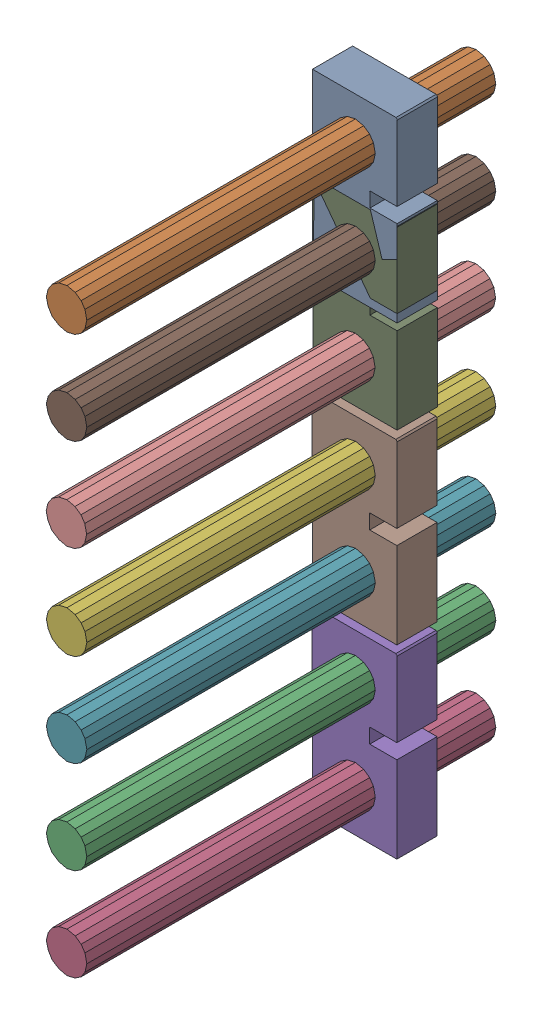
SolidWorks assembly P3, configuration Default. Lengths in mm.
Overall size (2.33 17.58 11.2).
22 component instances, 2 part files, 0 mates.
Components (placement in the parent):
- 432125072-1: 432125072 [Default] at (25.1917 44.8391 0) size (2.33 4.86 1.1)
  - Extruded (13)-1: Extruded (13) [Default] at origin size (2.33 4.86 1.1)
- 432124688-1: 432124688 [Default] at (25.1948 46.1265 -2.2) size (1.11 1.11 11.2)
  - Extruded (14)-1: Extruded (14) [Default] at origin size (1.11 1.11 11.2)
- 432124688_1-1: 432124688_1 [Default] at (25.1954 33.4054 -2.2) size (1.11 1.11 11.2)
  - Extruded (14)-1: Extruded (14) [Default] at origin size (1.11 1.11 11.2)
- 432124688_2-1: 432124688_2 [Default] at (25.1954 30.8654 -2.2) size (1.11 1.11 11.2)
  - Extruded (14)-1: Extruded (14) [Default] at origin size (1.11 1.11 11.2)
- 432125072_1-1: 432125072_1 [Default] at (25.1858 32.1222 0) size (2.33 4.86 1.1)
  - Extruded (13)-1: Extruded (13) [Default] at origin size (2.33 4.86 1.1)
- 432124688_3-1: 432124688_3 [Default] at (25.1954 38.4854 -2.2) size (1.11 1.11 11.2)
  - Extruded (14)-1: Extruded (14) [Default] at origin size (1.11 1.11 11.2)
- 432124688_4-1: 432124688_4 [Default] at (25.1954 35.9454 -2.2) size (1.11 1.11 11.2)
  - Extruded (14)-1: Extruded (14) [Default] at origin size (1.11 1.11 11.2)
- 432125072_2-1: 432125072_2 [Default] at (25.1858 37.2022 0) size (2.33 4.86 1.1)
  - Extruded (13)-1: Extruded (13) [Default] at origin size (2.33 4.86 1.1)
- 432125072_3-1: 432125072_3 [Default] at (25.1917 42.2991 0) size (2.33 4.86 1.1)
  - Extruded (13)-1: Extruded (13) [Default] at origin size (2.33 4.86 1.1)
- 432124688_5-1: 432124688_5 [Default] at (25.1901 41.0465 -2.2) size (1.11 1.11 11.2)
  - Extruded (14)-1: Extruded (14) [Default] at origin size (1.11 1.11 11.2)
- 432124688_6-1: 432124688_6 [Default] at (25.1948 43.5865 -2.2) size (1.11 1.11 11.2)
  - Extruded (14)-1: Extruded (14) [Default] at origin size (1.11 1.11 11.2)
